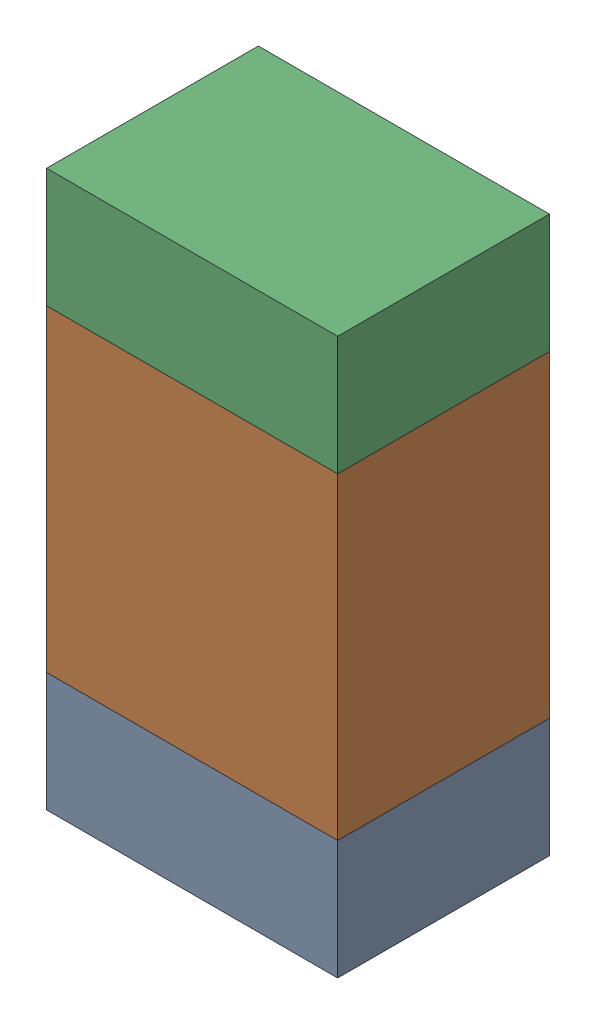
SolidWorks assembly R507_1PCB, configuration Default. Lengths in mm.
Overall size (0.55 1.05 0.4).
6 component instances, 2 part files, 0 mates.
Components (placement in the parent):
- 846483288-1: 846483288 [Default] at (147.4001 115.5874 0) size (0.55 0.22 0.4)
  - Extruded_12-1: Extruded_12 [Default] at origin size (0.55 0.22 0.4)
- 846483424-1: 846483424 [Default] at (147.4001 115.9999 0) size (0.55 0.6 0.4)
  - Extruded_13-1: Extruded_13 [Default] at origin size (0.55 0.6 0.4)
- 846483288-2: 846483288 [Default] at (147.4001 116.4124 0) size (0.55 0.22 0.4)
  - Extruded_12-1: Extruded_12 [Default] at origin size (0.55 0.22 0.4)
